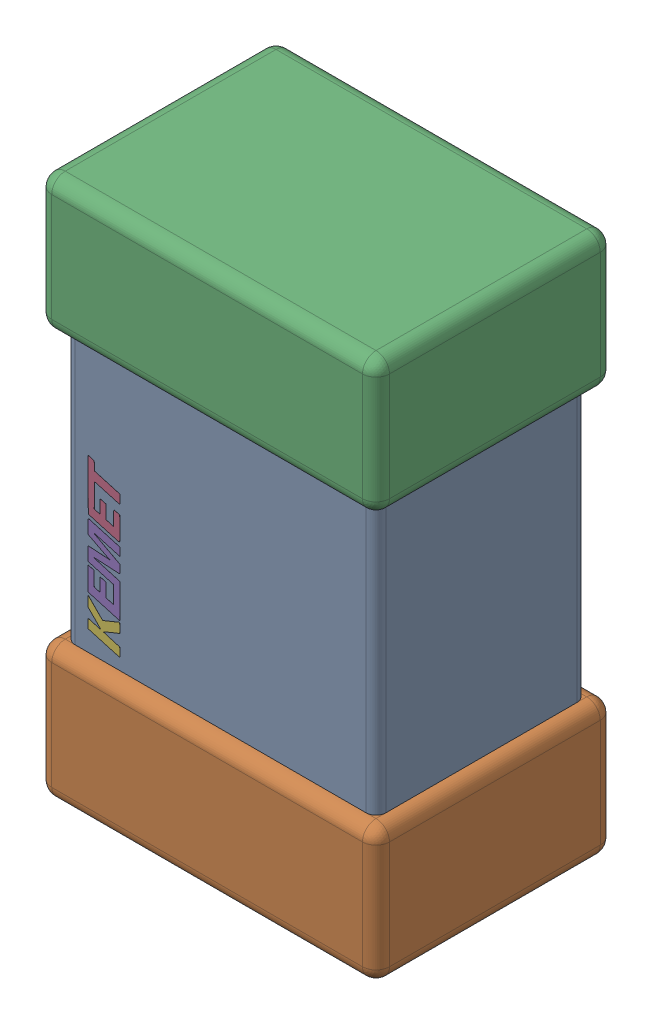
SolidWorks assembly C7.step, configuration Default. Lengths in mm.
Overall size (1.25 2 0.88).
3 component instances, 3 part files, 0 mates.
Components (placement in the parent):
- Cap_KEMET_C0805C472J3HAC_eec.step-1: Cap_KEMET_C0805C472J3HAC_eec.step [Default] at (39.326 65.924 0) x (0 1 0) z (0 0 1) size (1 1.15 0.78)
- Cap_KEMET_C0805C472J3HAC_eec-7.step-1: Cap_KEMET_C0805C472J3HAC_eec-7.step [Default] at (39.326 65.924 0) x (0 1 0) z (0 0 1) size (2 1.25 0.88)
- Cap_KEMET_C0805C472J3HAC_eec-8.step-1: Cap_KEMET_C0805C472J3HAC_eec-8.step [Default] at (39.326 65.924 0) x (0 1 0) z (0 0 1) size (0.59 0.12 0)
